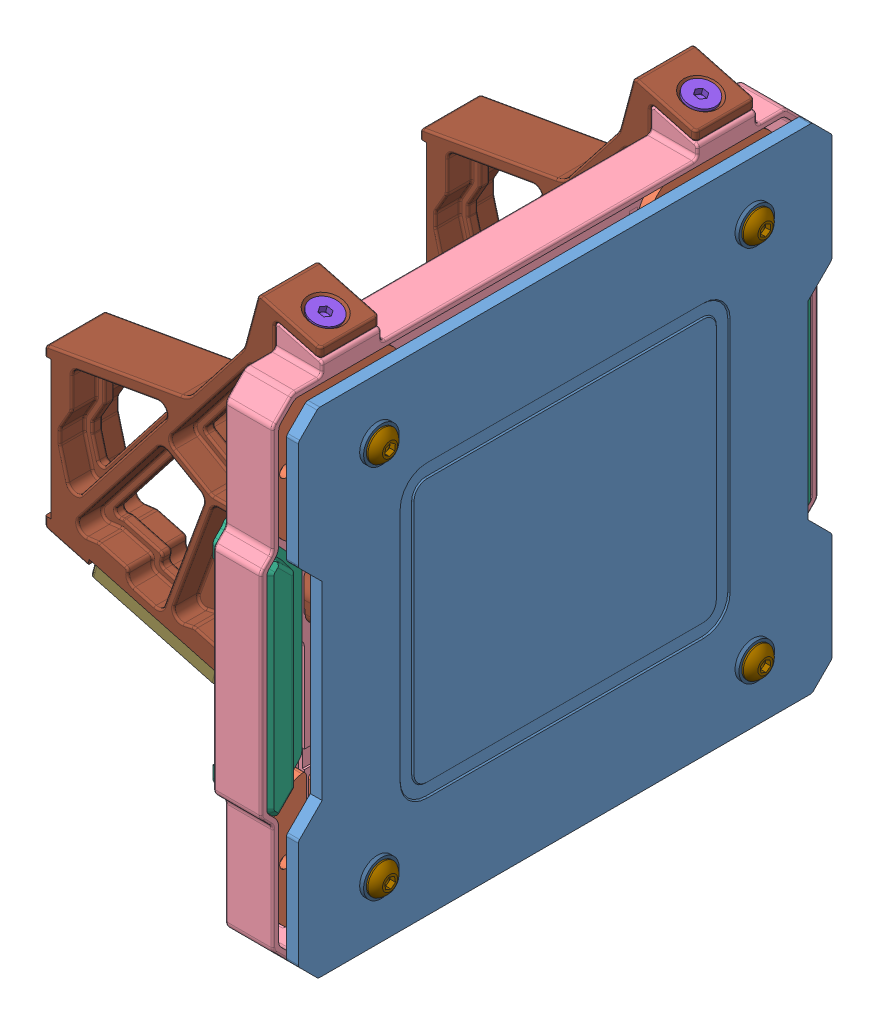
SolidWorks assembly 小装甲, configuration 默认. Lengths in mm.
Overall size (80.28 134.7 141).
37 component instances, 13 part files, 1 mates.
Components (placement in the parent):
- MK_前板2-1: MK_前板2 [默认] at (-23.3802 -2.5787 132) size (3 125 135)
- 微型压力传感器_1_2-1: 微型压力传感器_1_2 [默认] at (2.3698 -44.284 82.1087) x (0 0 1) z (-1 0 0) size (34 33.83 9.5)
  - CS_应变片-1: CS_应变片 [默认] at (2.3913 -0.6048 32.75) size (34 33.83 2.5)
  - CS_固定片1_2-1: CS_固定片1_2 [默认] at (2.3913 0.6952 32.75) x (0 0 -1) z (0 -1 0) size (9 10 26)
- 微型压力传感器_1_2-2: 微型压力传感器_1_2 [默认] at (2.3698 39.1265 86.8913) x (0 0 -1) z (-1 0 0) size (34 33.83 9.5)
  - CS_应变片-1: CS_应变片 [默认] at (2.3913 -0.6048 32.75) size (34 33.83 2.5)
  - CS_固定片1_2-1: CS_固定片1_2 [默认] at (2.3913 0.6952 32.75) x (0 0 -1) z (0 -1 0) size (9 10 26)
- 微型压力传感器_1_2-3: 微型压力传感器_1_2 [默认] at (2.3698 39.1265 181.8913) x (0 0 -1) z (-1 0 0) size (34 33.83 9.5)
  - CS_应变片-1: CS_应变片 [默认] at (2.3913 -0.6048 32.75) size (34 33.83 2.5)
  - CS_固定片1_2-1: CS_固定片1_2 [默认] at (2.3913 0.6952 32.75) x (0 0 -1) z (0 -1 0) size (9 10 26)
- 微型压力传感器_1_2-4: 微型压力传感器_1_2 [默认] at (2.3698 -44.284 177.1087) x (0 0 1) z (-1 0 0) size (34 33.83 9.5)
  - CS_应变片-1: CS_应变片 [默认] at (2.3913 -0.6048 32.75) size (34 33.83 2.5)
  - CS_固定片1_2-1: CS_固定片1_2 [默认] at (2.3913 0.6952 32.75) x (0 0 -1) z (0 -1 0) size (9 10 26)
- MK_后板3_2_2-1: MK_后板3_2_2 [默认] at (-38.8802 -2.5787 132) size (12 130.91 141)
- MK_灯条-1: MK_灯条 [默认] at (-31.1802 -2.5787 196.5) x (-1 0 0) z (0 1 0) size (1.98 8 45)
- MK_导光条2s-1: MK_导光条2s [默认] at (-40.6397 -2.5787 132) x (0 0 -1) z (1 0 0) size (12 59.61 14.5)
- 四路板子-1: 四路板子 [默认] at (-33.8802 -2.5787 132) x (1 0 0) z (0 1 0) size (9.7 55 45)
- socket countersunk head screw_iso_ISO 10642 - M4 x 8 --- 8N-1: socket countersunk head screw_iso_ISO 10642 - M4 x 8 --- 8N [默认] at (-33.4776 67.2772 84.5) x (-0.258819 -0.965926 0) z (-0.811347 0.2174 0.542635) size (8 7.53 7.53)
- socket countersunk head screw_iso_ISO 10642 - M4 x 8 --- 8N-2: socket countersunk head screw_iso_ISO 10642 - M4 x 8 --- 8N [默认] at (-33.5475 67.0164 179.5) x (-0.258819 -0.965926 0) z (-0.811347 0.2174 0.542635) size (8 7.53 7.53)
- socket button head screw_iso_ISO 7380 - M4 x 8 --- 8N-1: socket button head screw_iso_ISO 7380 - M4 x 8 --- 8N [默认] at (-17.1802 45.4463 84.5) x (-1 0 0) z (0 -0.06101 0.998137) size (10.64 7.69 7.66)
- socket button head screw_iso_ISO 7380 - M4 x 8 --- 8N-2: socket button head screw_iso_ISO 7380 - M4 x 8 --- 8N [默认] at (-17.1802 -50.0764 179.5) x (-1 0 0) z (0 -0.935077 0.354444) size (10.64 7.69 7.66)
- socket button head screw_iso_ISO 7380 - M4 x 8 --- 8N-3: socket button head screw_iso_ISO 7380 - M4 x 8 --- 8N [默认] at (-17.1802 -50.0764 84.5) x (-1 0 0) z (0 0.8108 0.585323) size (10.64 7.69 7.66)
- socket button head screw_iso_ISO 7380 - M4 x 8 --- 8N-4: socket button head screw_iso_ISO 7380 - M4 x 8 --- 8N [默认] at (-17.1802 44.9189 179.5) x (-1 0 0) z (0 -0.91596 -0.401269) size (10.64 7.69 7.66)
- plain washer 10673 type snl_iso_ISO 10673-4.55-S-1: plain washer 10673 type snl_iso_ISO 10673-4.55-S [默认] at (-20.3802 45.4463 84.5) size (1 9 9)
- plain washer 10673 type snl_iso_ISO 10673-4.55-S-2: plain washer 10673 type snl_iso_ISO 10673-4.55-S [默认] at (-20.3802 -50.0764 84.5) size (1 9 9)
- plain washer 10673 type snl_iso_ISO 10673-4.55-S-3: plain washer 10673 type snl_iso_ISO 10673-4.55-S [默认] at (-20.3802 -50.0764 179.5) x (1 0 0) z (0 -0.254234 0.967143) size (1 9 9)
- plain washer 10673 type snl_iso_ISO 10673-4.55-S-4: plain washer 10673 type snl_iso_ISO 10673-4.55-S [默认] at (-20.3802 44.9189 179.5) size (1 9 9)
- MK_灯条-2: MK_灯条 [默认] at (-31.1802 -2.5787 67.5) x (-1 0 0) z (0 -1 0) size (1.98 8 45)
- ZJ7_支撑架-1: ZJ7_支撑架 [默认] at (-38.8802 -23.8633 84.5) x (0 0 -1) z (1 0 0) size (15.02 127.12 69.65)
- ZJ7_支撑架-2: ZJ7_支撑架 [默认] at (-38.8802 -23.8633 179.5) x (0 0 -1) z (1 0 0) size (15.02 127.12 69.65)
- MK_橡胶垫-1: MK_橡胶垫 [默认] at (-34.457 -23.4956 84.5) x (0 0 1) z (-0.258819 -0.965926 0) size (15 33 5.5)
- MK_橡胶垫-2: MK_橡胶垫 [默认] at (-34.457 -23.4956 179.5) x (0 0 1) z (-0.258819 -0.965926 0) size (15 33 5.5)
- MK_橡胶套-1: MK_橡胶套 [默认] at (-37.3802 17.9213 106.5) x (0 -0.210884 -0.977511) z (1 0 0) size (7 7 4)
- MK_橡胶套-2: MK_橡胶套 [默认] at (-37.3802 -23.0787 106.5) x (0 -0.210884 -0.977511) z (1 0 0) size (7 7 4)
- MK_橡胶套-3: MK_橡胶套 [默认] at (-37.3802 17.9213 157.5) x (0 -0.210884 -0.977511) z (1 0 0) size (7 7 4)
- MK_橡胶套-4: MK_橡胶套 [默认] at (-37.3802 -23.0787 157.5) x (0 -0.210884 -0.977511) z (1 0 0) size (7 7 4)
- MK_导光条2s-3: MK_导光条2s [默认] at (-40.6397 -2.5787 132) x (0 0 1) z (1 0 0) size (12 59.61 14.5)
Mates (geometry in assembly coordinates):
- 重合1: coincident aligned: plane of MK_导光条2s-1 through (-26.1397 -2.5787 132) normal (1 0 0); plane of ? through (-26.1397 -14.2279 124.9852) normal (1 0 0)
